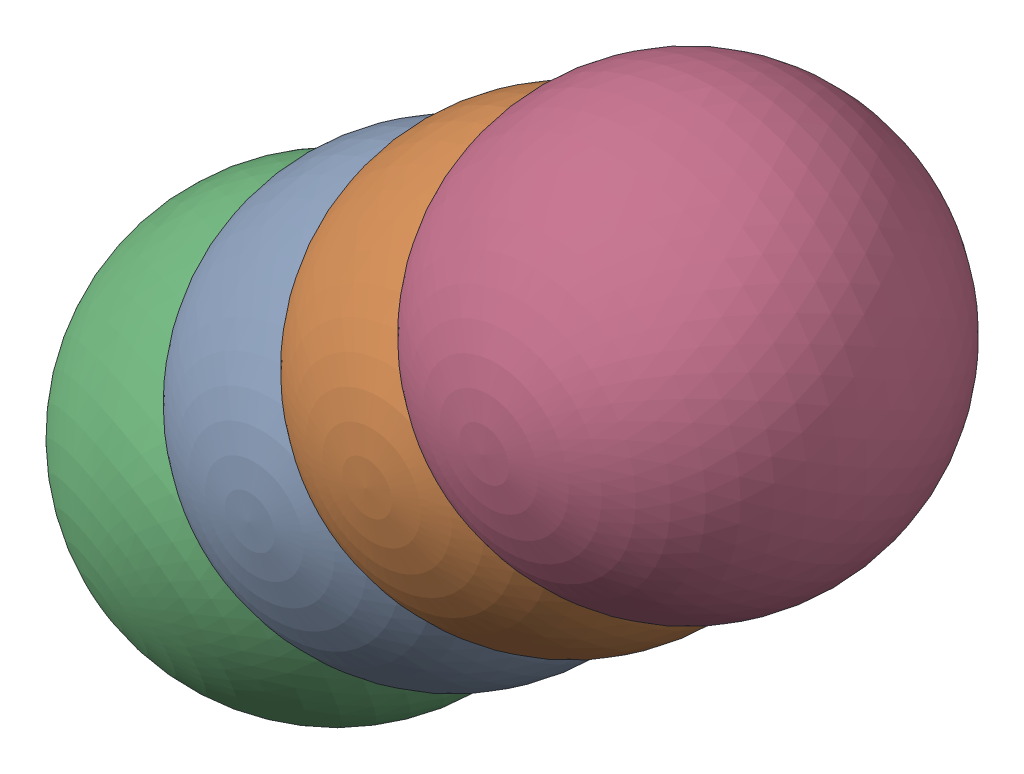
SolidWorks assembly Assem7, configuration Default. Lengths in mm.
Overall size (197.77 184.43 148.49).
4 component instances, 1 part files, 4 mates.
Components (placement in the parent):
- secondhalfpart1-5: secondhalfpart1 [Default] at (-48.0249 6.0494 60) size (60 60 60)
- secondhalfpart1-6: secondhalfpart1 [Default] at (-7.0114 42.7606 83.8784) size (60 60 60)
- secondhalfpart1-7: secondhalfpart1 [Default] at (-97.3425 -42.7188 32.3069) x (0.912105 0.17596 0.370275) z (-0.276803 -0.4019 0.872844) size (60 60 60)
- secondhalfpart1-8: secondhalfpart1 [Default] at (33.9889 79.4689 107.7839) size (60 60 60)
Mates (geometry in assembly coordinates):
- Tangent1: tangent anti-aligned: sphere of secondhalfpart1-6; sphere of secondhalfpart1-8
- Tangent2: tangent anti-aligned: sphere of secondhalfpart1-5; sphere of secondhalfpart1-6
- Tangent3: tangent anti-aligned: sphere of secondhalfpart1-5; sphere of secondhalfpart1-7
- Distance1: distance = 120 mm anti-aligned: sphere of secondhalfpart1-8; sphere of secondhalfpart1-7
